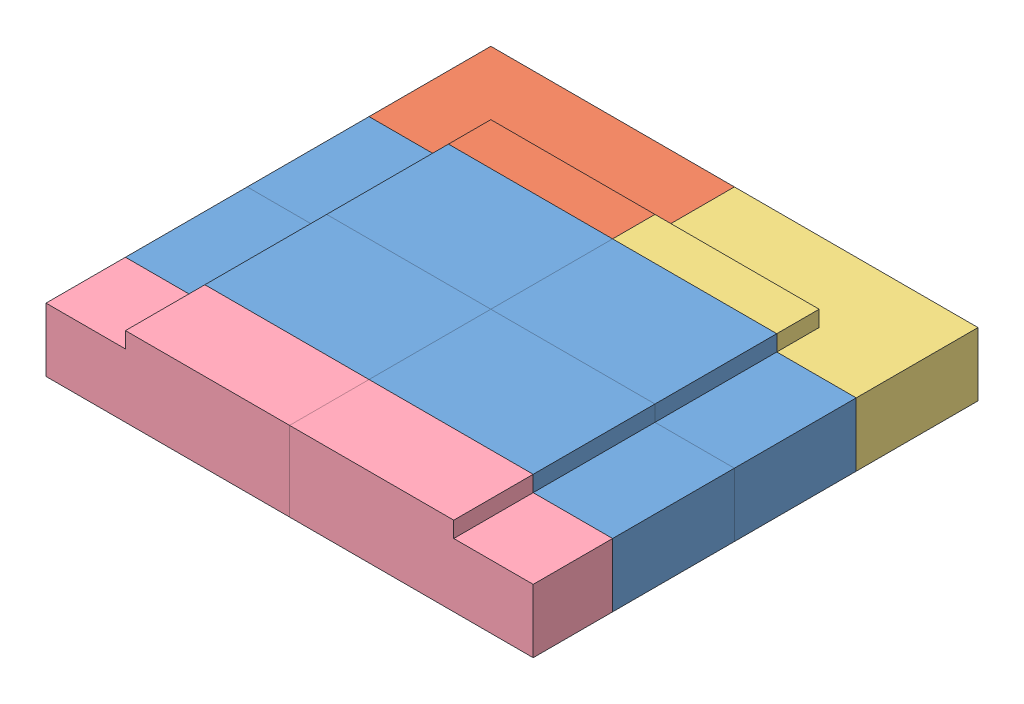
SolidWorks assembly Heat Treat Asm Top-Bot, configuration Default. Lengths in mm.
Overall size (460 75 420).
8 component instances, 4 part files, 14 mates.
Components (placement in the parent):
- Brick-Sharp-BackCut-1: Brick-Sharp-BackCut [Default] at (63.541 113.2041 192.9534) size (230 75 115)
- Brick-Sharp-BackRightCut-1: Brick-Sharp-BackRightCut [Default] at (63.541 113.2041 77.9534) size (230 75 115)
- Brick-Sharp-BackLeftCut-2: Brick-Sharp-BackLeftCut [Default] at (293.541 113.2041 77.9534) x (-1 0 0) z (0 0 -1) size (230 75 115)
- Brick-Sharp-BackCut-2: Brick-Sharp-BackCut [Default] at (63.541 113.2041 307.9534) size (230 75 115)
- Brick-Sharp-BackCut-4: Brick-Sharp-BackCut [Default] at (293.541 113.2041 192.9534) x (-1 0 0) z (0 0 -1) size (230 75 115)
- Brick-Sharp-BackCut-5: Brick-Sharp-BackCut [Default] at (293.541 113.2041 307.9534) x (-1 0 0) z (0 0 -1) size (230 75 115)
- Brick-Sharp-BackCutTrimmed-1: Brick-Sharp-BackCutTrimmed [Default] at (63.541 113.2041 422.9534) size (230 75 75)
- Brick-Sharp-BackCutTrimmed-2: Brick-Sharp-BackCutTrimmed [Default] at (293.541 113.2041 382.9534) x (-1 0 0) z (0 0 -1) size (230 75 75)
Mates (geometry in assembly coordinates):
- Coincident5: coincident anti-aligned: plane of Brick-Sharp-BackCut-1 through (178.541 150.7041 135.4534) normal (1 0 0); plane of Brick-Sharp-BackCut-4 through (178.541 150.7041 250.4534) normal (-1 0 0)
- Parallel1: parallel: plane of Brick-Sharp-BackCut-1 through (63.541 150.7041 192.9534) normal (0 1 0); line of Brick-Sharp-BackCut-4 through (178.541 150.7041 135.4534) axis (0 0 1)
- Coincident7: coincident aligned: line of Brick-Sharp-BackCut-1 through (178.541 150.7041 135.4534) axis (0 -1 0); line of Brick-Sharp-BackCut-4 through (178.541 150.7041 135.4534) axis (0 -1 0)
- Coincident8: coincident anti-aligned: line of Brick-Sharp-BackCut-1 through (178.541 75.7041 250.4534) axis (0 0 -1); line of Brick-Sharp-BackCut-4 through (178.541 75.7041 135.4534) axis (0 0 1)
- Coincident9: coincident anti-aligned: plane of Brick-Sharp-BackLeftCut-2 through (408.541 150.7041 135.4534) normal (0 0 1); plane of Brick-Sharp-BackCut-4 through (408.541 150.7041 135.4534) normal (0 0 -1)
- Coincident10: coincident: point of Brick-Sharp-BackLeftCut-2; unknown of Brick-Sharp-BackCut-4
- Coincident11: coincident anti-aligned: line of Brick-Sharp-BackLeftCut-2 through (178.541 150.7041 135.4534) axis (1 0 0); line of Brick-Sharp-BackCut-4 through (333.541 150.7041 135.4534) axis (-1 0 0)
- Coincident12: coincident anti-aligned: plane of Brick-Sharp-BackRightCut-1 through (178.541 150.7041 20.4534) normal (1 0 0); plane of Brick-Sharp-BackLeftCut-2 through (178.541 150.7041 135.4534) normal (-1 0 0)
- Coincident13: coincident: point of Brick-Sharp-BackRightCut-1; point of Brick-Sharp-BackLeftCut-2
- Coincident14: coincident anti-aligned: plane of Brick-Sharp-BackCutTrimmed-1 through (178.541 150.7041 365.4534) normal (1 0 0); plane of Brick-Sharp-BackCutTrimmed-2 through (178.541 150.7041 440.4534) normal (-1 0 0)
- Coincident15: coincident anti-aligned: line of Brick-Sharp-BackCutTrimmed-1 through (178.541 150.7041 440.4534) axis (0 0 -1); line of Brick-Sharp-BackCutTrimmed-2 through (178.541 150.7041 365.4534) axis (0 0 1)
- Coincident16: coincident anti-aligned: line of Brick-Sharp-BackCutTrimmed-1 through (178.541 75.7041 440.4534) axis (0 1 0); line of Brick-Sharp-BackCutTrimmed-2 through (178.541 150.7041 440.4534) axis (0 -1 0)
- Coincident18: coincident anti-aligned: plane of Brick-Sharp-BackCut-2 through (-51.459 150.7041 365.4534) normal (0 0 1); plane of Brick-Sharp-BackCutTrimmed-1 through (-51.459 150.7041 365.4534) normal (0 0 -1)
- Coincident19: coincident aligned: line of Brick-Sharp-BackCut-2 through (-51.459 75.7041 250.4534) axis (0 0 1); line of Brick-Sharp-BackCutTrimmed-1 through (-51.459 75.7041 365.4534) axis (0 0 1)
